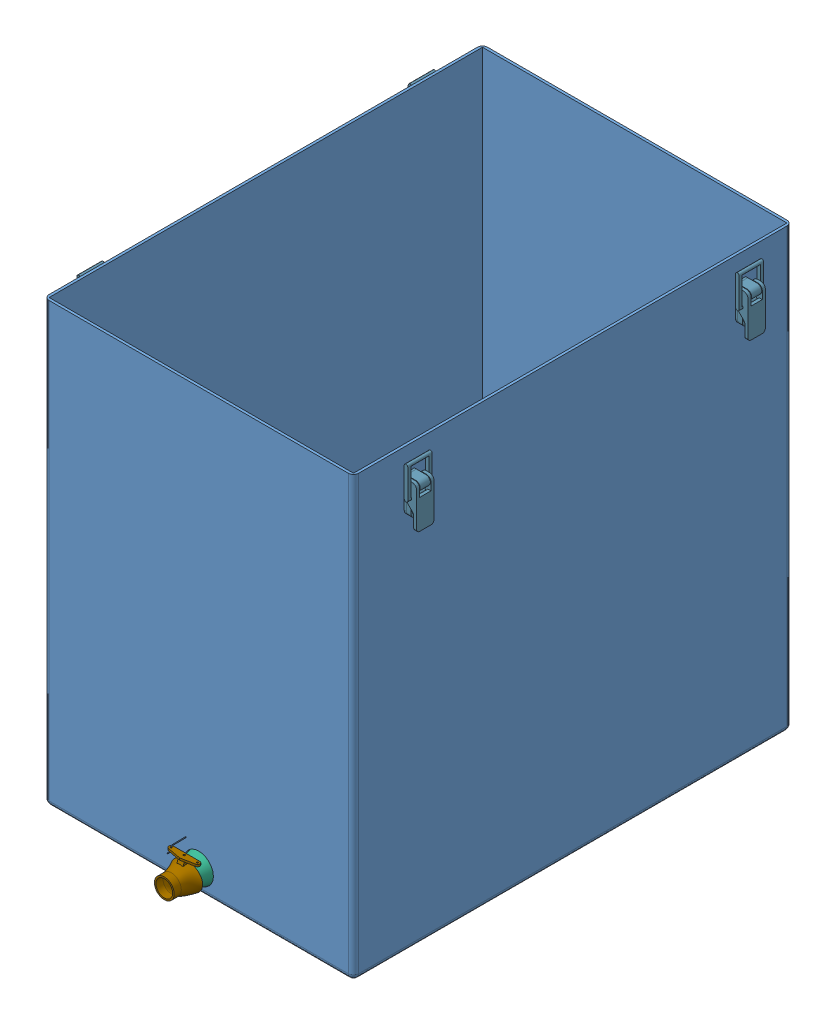
SolidWorks assembly impeller_styrofoam sub assy, configuration Default. Lengths in mm.
Overall size (336.3 431.8 465.68).
22 component instances, 15 part files, 18 mates.
Components (placement in the parent):
- styrofoam impeller mount-1: styrofoam impeller mount [Default] at (-143.924 -118.1594 -226.3788) size (304.8 431.8 431.8)
- assembly 25mm impeller jet drive-1: assembly 25mm impeller jet drive [Default] at (8.466 -96.2939 191.7462) x (0 0 1) z (-1 0 0) size (175.66 47.97 37.3)
  - jet drive for 25mm impeller-1: jet drive for 25mm impeller [Default] at (-2.105 -21.3255 0) size (90 39.15 37)
  - shaft-1: shaft [Default] at (-69.955 -0.679 0) x (1 0 0) z (0 -0.374675 0.927156) size (85 3 3)
  - RS365 DC Motor-1: RS365 DC Motor [Default] at (-77.105 -0.679 0) x (1 0 0) z (0 1 0) size (51 27.5 27.5)
  - shaft coupler-1: shaft coupler [Default] at (-63.411 -0.679 0) x (-1 0 0) z (0 -0.042922 -0.999078) size (20 9 9)
  - stator-1: stator [Default] at (-4.955 -0.679 0) size (35.93 37.32 37.3)
  - impeller 25min OD-1: impeller 25min OD [Default] at (11.045 -0.679 0) x (0 0.907746 0.419521) z (0 -0.419521 0.907746) size (24.22 20 24.19)
  - servo towerpro sg90-1: servo towerpro sg90 [Default] at (-55.63 10.746 -16.6125) x (1 0 0) z (0 -1 0) size (32.05 31 21.88)
  - nozzle-1: nozzle [Default] at (25.545 -0.679 0) x (0 0 -1) z (0 -1 0) size (31.46 22.02 31.51)
  - wire-1: wire [Default] at origin size (95.63 10.1 6.02)
  - bearing-1: bearing [Default] at (-48.4939 -0.679 0) x (0 -0.407486 -0.913211) z (-1 0 0) size (4 4 4)
  - bearing-2: bearing [Default] at (-58.105 -0.679 0) x (0 0.170235 0.985404) z (-1 0 0) size (4 4 4)
  - bearing-3: bearing [Default] at (15.045 -0.679 0) x (0 0.944365 0.328901) z (-1 0 0) size (4 4 4)
  - hull-1: hull [Default] at origin size (333.75 30.44 61.92) (hidden)
  - pan head cross recess screw_iso-1: pan head cross recess screw_iso [ISO 7045 - M2.5 x 5 - Z - 5N] at (-87.155 -0.679 8) x (-1 0 0) z (0 -0.924225 -0.381849) size (7.05 5 5)
  - pan head cross recess screw_iso-2: pan head cross recess screw_iso [ISO 7045 - M2.5 x 5 - Z - 5N] at (-87.155 -0.679 -8) x (-1 0 0) z (0 -0.85199 -0.523557) size (7.05 5 5)
  - countersunk flat head cross recess screw_iso-2: countersunk flat head cross recess screw_iso [ISO 7046-1 - M2.5 x 5 - Z - 5N] at (-92.105 -13.679 0) size (5 4.7 4.7)
- latch_thrusterbin-1: latch_thrusterbin [Default] at (176.626 356.9025 -150.495) x (0 -1 0) z (1 0 0) size (57 24 15.75)
- latch_thrusterbin-2: latch_thrusterbin [Default] at (176.626 356.9025 175.7459) x (0 -1 0) z (1 0 0) size (57 24 15.75)
- latch_thrusterbin-4: latch_thrusterbin [Default] at (-159.674 356.9025 125.1971) x (0 -1 0) z (-1 0 0) size (57 24 15.75)
- latch_thrusterbin-5: latch_thrusterbin [Default] at (-159.674 356.9025 -201.0438) x (0 -1 0) z (-1 0 0) size (57 24 15.75)
Mates (geometry in assembly coordinates):
- Parallel1: parallel anti-aligned: line of styrofoam impeller mount-1 through (-141.384 313.6406 202.8812) axis (1 0 0); line of assembly 25mm impeller jet drive-1/jet drive for 25mm impeller-1 through (26.966 -115.6194 189.6412) axis (-1 0 0)
- Coincident3: coincident anti-aligned: plane of styrofoam impeller mount-1 through (-143.924 -115.6194 205.4212) normal (0 1 0); plane of assembly 25mm impeller jet drive-1/jet drive for 25mm impeller-1 through (8.466 -115.6194 144.6412) normal (0 -1 0)
- Coincident4: coincident anti-aligned: plane of styrofoam impeller mount-1 through (-8.034 -118.1594 187.6412) normal (1 0 0); plane of assembly 25mm impeller jet drive-1/jet drive for 25mm impeller-1 through (-8.034 -115.6194 187.6412) normal (-1 0 0)
- Coincident6: coincident: line of styrofoam impeller mount-1 through (24.986 -118.1594 187.6412) axis (0 1 0); plane of assembly 25mm impeller jet drive-1/jet drive for 25mm impeller-1 through (24.966 -115.6194 187.6412) normal (0 0 1)
- Parallel2: parallel anti-aligned: line of styrofoam impeller mount-1 through (-141.384 313.6406 202.8812) axis (1 0 0); line of assembly 25mm impeller jet drive-2/jet drive for 25mm impeller-1 through (289.856 -110.5394 189.6412) axis (-1 0 0)
- Coincident7: coincident anti-aligned: plane of styrofoam impeller mount-1 through (-143.924 -110.5394 205.4212) normal (0 1 0); plane of assembly 25mm impeller jet drive-2/jet drive for 25mm impeller-1 through (271.356 -110.5394 144.6412) normal (0 -1 0)
- Coincident8: coincident anti-aligned: plane of styrofoam impeller mount-1 through (254.856 -118.1594 187.6412) normal (1 0 0); plane of assembly 25mm impeller jet drive-2/jet drive for 25mm impeller-1 through (254.856 -110.5394 187.6412) normal (-1 0 0)
- Coincident9: coincident anti-aligned: plane of styrofoam impeller mount-1 through (287.876 -118.1594 187.6412) normal (0 0 -1); plane of assembly 25mm impeller jet drive-2/jet drive for 25mm impeller-1 through (287.856 -110.5394 187.6412) normal (0 0 1)
- Coincident10: coincident anti-aligned: plane of styrofoam impeller mount-1 through (160.876 -118.1594 205.4212) normal (1 0 0); plane of latch_thrusterbin-1 through (160.876 259.7806 -175.7694) normal (-1 0 0)
- Distance1: distance = 22.86 mm aligned: plane of styrofoam impeller mount-1 through (-143.924 313.6406 205.4212) normal (0 1 0); plane of latch_thrusterbin-1 through (160.876 290.7806 -170.7694) normal (0 1 0)
- Coincident12: coincident anti-aligned: plane of styrofoam impeller mount-1 through (160.876 -118.1594 205.4212) normal (1 0 0); plane of latch_thrusterbin-2 through (160.876 259.7806 150.4715) normal (-1 0 0)
- Distance2: distance = 22.86 mm aligned: plane of styrofoam impeller mount-1 through (-143.924 313.6406 205.4212) normal (0 1 0); plane of latch_thrusterbin-2 through (160.876 290.7806 155.4715) normal (0 1 0)
- Coincident14: coincident anti-aligned: plane of styrofoam impeller mount-1 through (-143.924 -118.1594 205.4212) normal (-1 0 0); plane of latch_thrusterbin-4 through (-143.924 259.7806 150.4715) normal (1 0 0)
- Distance4: distance = 22.86 mm aligned: plane of styrofoam impeller mount-1 through (-143.924 313.6406 205.4212) normal (0 1 0); plane of latch_thrusterbin-4 through (-143.924 290.7806 145.4715) normal (0 1 0)
- Distance5: distance = 22.86 mm aligned: plane of styrofoam impeller mount-1 through (-143.924 313.6406 205.4212) normal (0 1 0); plane of latch_thrusterbin-5 through (-143.924 290.7806 -180.7694) normal (0 1 0)
- Coincident15: coincident anti-aligned: plane of styrofoam impeller mount-1 through (-143.924 -118.1594 205.4212) normal (-1 0 0); plane of latch_thrusterbin-5 through (-143.924 259.7806 -175.7694) normal (1 0 0)
- Coincident16: coincident aligned: plane of latch_thrusterbin-2 through (160.876 290.7806 155.4715) normal (0 0 1); plane of latch_thrusterbin-4 through (-143.924 290.7806 155.4715) normal (0 0 1)
- Coincident17: coincident aligned: plane of latch_thrusterbin-1 through (160.876 290.7806 -170.7694) normal (0 0 1); plane of latch_thrusterbin-5 through (-143.924 290.7806 -170.7694) normal (0 0 1)
